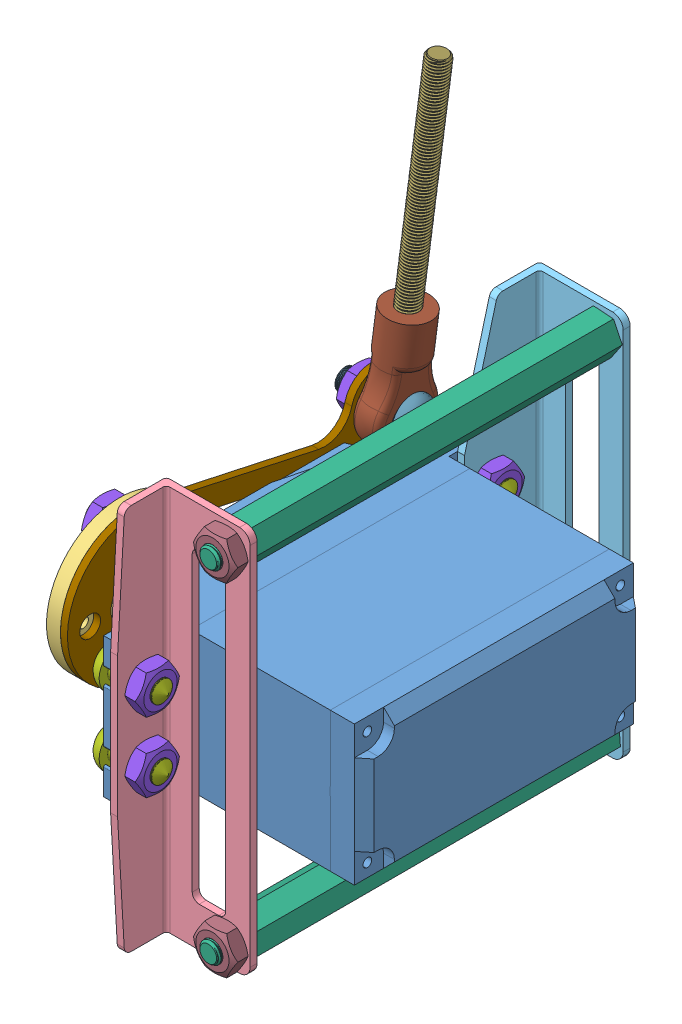
SolidWorks assembly 舵机装配, configuration 默认. Lengths in mm.
Overall size (50 100.66 64.22).
33 component instances, 14 part files, 67 mates.
Components (placement in the parent):
- 舵机-1: 舵机 [默认] at (-7.7618 -11.8937 34.529) size (40 20.22 54.02)
- 舵机齿轮-1: 舵机齿轮 [默认] at (-25.7618 -11.8937 63.729) x (0 0 -1) z (1 0 0) size (5.77 5.77 4)
- 舵机摆臂连接件-1: 舵机摆臂连接件 [默认] at (-23.2618 -11.8937 63.729) x (0 -0.05131 0.998683) z (-1 0 0) size (21 21 6.01)
- 舵机支架-上-1: 舵机支架-上 [默认] at (2.2382 -11.8937 75.034) x (0 1 0) z (0 0 1) size (55.4 13 8)
- 舵机支架-下-1: 舵机支架-下 [默认] at (2.2382 -11.8937 21.534) x (0 1 0) z (0 0 1) size (55.4 13 11.75)
- 铜柱-舵机-1: 铜柱-舵机 [默认] at (-0.7618 -36.3937 22.534) x (0.003125 0.999995 0) z (0 0 1) size (5.75 5.22 56.58)
- 铜柱-舵机-2: 铜柱-舵机 [默认] at (-0.7618 12.6063 22.534) x (0.625891 0.77991 0) z (0 0 1) size (5.75 5.22 56.58)
- 十字半圆头螺钉-M3-1: 十字半圆头螺钉-M3 [GB_WOOD_SCREWS_TYPE136 M3X8-N] at (-15.6318 -6.8937 79.284) size (9.31 5.8 5.8)
- 十字半圆头螺钉-M3-3: 十字半圆头螺钉-M3 [GB_WOOD_SCREWS_TYPE136 M3X8-N] at (-15.6318 -16.8937 79.284) size (9.31 5.8 5.8)
- 十字半圆头螺钉-M3-4: 十字半圆头螺钉-M3 [GB_WOOD_SCREWS_TYPE136 M3X8-N] at (-15.6318 -6.8937 29.784) size (9.31 5.8 5.8)
- 十字半圆头螺钉-M3-5: 十字半圆头螺钉-M3 [GB_WOOD_SCREWS_TYPE136 M3X8-N] at (-15.6318 -16.8937 29.784) size (9.31 5.8 5.8)
- 六角螺母-M3-4: 六角螺母-M3 [GB_FASTENER_NUT_SNAB1 M3-C] at (-7.3618 -6.8937 29.784) x (0 0 -1) z (1 0 0) size (6.35 5.5 2.4)
- 六角螺母-M3-5: 六角螺母-M3 [GB_FASTENER_NUT_SNAB1 M3-C] at (-7.3618 -16.8937 29.784) x (0 0 -1) z (1 0 0) size (6.35 5.5 2.4)
- 六角螺母-M3-6: 六角螺母-M3 [GB_FASTENER_NUT_SNAB1 M3-C] at (-7.3618 -16.8937 79.284) x (0 0 -1) z (1 0 0) size (6.35 5.5 2.4)
- 六角螺母-M3-7: 六角螺母-M3 [GB_FASTENER_NUT_SNAB1 M3-C] at (-7.3618 -6.8937 79.284) x (0 0 -1) z (1 0 0) size (6.35 5.5 2.4)
- 舵机拉杆-1: 舵机拉杆 [默认] at (-26.7618 -10.1235 29.2744) x (0 0.998683 0.05131) z (1 0 0) size (21 49 1)
- 十字半圆头螺钉-M3-8: 十字半圆头螺钉-M3 [GB_WOOD_SCREWS_TYPE136 M3X8-N] at (-30.1318 -11.8937 63.729) size (9.31 5.8 5.8)
- 半球型活动头-1: 半球型活动头 [默认] at (-23.3618 -3.5233 26.8764) x (0 -0.381849 0.924225) z (0 0.924225 0.381849) size (5.8 4.8 5.8)
- 舵机拉杆球头-1: 舵机拉杆球头 [默认] at (-23.3618 -4.6307 29.5566) x (-0.080816 -0.995071 0.057468) z (-0.006326 0.058167 0.998287) size (17.5 6.4 9.4)
- 半球型活动头-2: 半球型活动头 [默认] at (-23.3618 -13.0321 27.676) x (0 -0.891063 0.453879) z (0 -0.453879 -0.891063) size (5.8 4.8 5.8)
- 舵机拉杆球头-2: 舵机拉杆球头 [默认] at (-23.3618 -15.6162 28.9922) x (-0.033008 0.983548 0.177606) z (-0.09339 -0.179961 0.979231) size (17.5 6.4 9.4)
- 丝杆-舵机-1: 丝杆-舵机 [默认] at (-19.7413 39.9485 26.9821) x (-0.977477 0.090401 0.1907) z (0.080816 0.995071 -0.057468) size (3.06 3.46 35.46)
- 丝杆-舵机-2: 丝杆-舵机 [默认] at (-23.0383 -25.255 27.2517) x (0.908978 -0.04434 0.41448) z (-0.033008 0.983548 0.177606) size (3.06 3.46 35.46)
- 六角螺母-M3-黄色-1: 六角螺母-M3-黄色 [GB_FASTENER_NUT_SNAB1 M3-C] at (-0.7618 12.6063 78.434) size (6.35 5.5 2.4)
- 六角螺母-M3-黄色-2: 六角螺母-M3-黄色 [GB_FASTENER_NUT_SNAB1 M3-C] at (-0.7618 -36.3937 78.434) size (6.35 5.5 2.4)
- 十字半圆头螺钉-M3-12: 十字半圆头螺钉-M3 [GB_WOOD_SCREWS_TYPE136 M3X8-N] at (-23.3918 -4.6532 64.101) x (-1 0 0) z (0 0.924225 0.381849) size (9.31 5.8 5.8)
- 六角螺母-M3-14: 六角螺母-M3 [GB_FASTENER_NUT_SNAB1 M3-C] at (-31.1618 -4.6532 64.101) x (0 0 1) z (-1 0 0) size (6.35 5.5 2.4)
- 十字半圆头长螺钉-M3-3: 十字半圆头长螺钉-M3 [GB_WOOD_SCREWS_TYPE136 M3X8-N] at (-18.5918 -4.6307 29.5566) x (-1 0 0) z (0 0.924225 0.381849) size (12.81 5.8 5.8)
- 十字半圆头长螺钉-M3-4: 十字半圆头长螺钉-M3 [GB_WOOD_SCREWS_TYPE136 M3X8-N] at (-18.5918 -15.6162 28.9922) x (-1 0 0) z (0 0.924225 0.381849) size (12.81 5.8 5.8)
- 六角螺母-M3-16: 六角螺母-M3 [GB_FASTENER_NUT_SNAB1 M3-C] at (-29.1618 -4.6307 29.5566) x (0 0 1) z (-1 0 0) size (6.35 5.5 2.4)
- 六角螺母-M3-17: 六角螺母-M3 [GB_FASTENER_NUT_SNAB1 M3-C] at (-29.1618 -15.6162 28.9922) x (0 0 1) z (-1 0 0) size (6.35 5.5 2.4)
- 十字半圆头螺钉-M3-14: 十字半圆头螺钉-M3 [GB_WOOD_SCREWS_TYPE136 M3X8-N] at (-23.3918 -19.1341 63.357) x (-1 0 0) z (0 0.924225 0.381849) size (9.31 5.8 5.8)
- 六角螺母-M3-18: 六角螺母-M3 [GB_FASTENER_NUT_SNAB1 M3-C] at (-31.1618 -19.1341 63.357) x (0 0 1) z (-1 0 0) size (6.35 5.5 2.4)
Mates (geometry in assembly coordinates):
- 重合1: coincident anti-aligned: plane of 舵机-1 through (-21.7618 -11.8937 63.729) normal (-1 0 0); plane of 舵机齿轮-1 through (-21.7618 -11.8937 63.729) normal (1 0 0)
- 同心2: concentric aligned: cylinder of 舵机-1 through (-21.7618 -11.8937 63.729) axis (-1 0 0) radius 2.95; cylinder of 舵机齿轮-1 through (-25.7618 -11.8937 63.729) axis (-1 0 0) radius 0.875
- 平行1: parallel anti-aligned: plane of 舵机齿轮-1 through (-25.7618 -11.8937 63.729) normal (-1 0 0); plane of 舵机摆臂连接件-1 through (-26.7618 -11.8937 63.729) normal (1 0 0)
- 距离1: distance = 46 mm anti-aligned: plane of 舵机摆臂连接件-1 through (-28.7618 -11.8937 63.729) normal (-1 0 0); plane of 舵机-1 through (17.2382 -1.8837 35.779) normal (1 0 0)
- 同心3: concentric aligned: cylinder of 舵机齿轮-1 through (-25.7618 -11.8937 63.729) axis (-1 0 0) radius 0.875; cylinder of 舵机摆臂连接件-1 through (-26.7618 -11.8937 63.729) axis (-1 0 0) radius 1.5
- 同心4: concentric anti-aligned: cylinder of 舵机-1 through (12.2392 -16.8937 29.784) axis (-1 0 0) radius 2.25; cylinder of 舵机支架-下-1 through (-10.7618 -16.8937 29.784) axis (1 0 0) radius 1.5
- 重合3: coincident anti-aligned: plane of 舵机支架-下-1 through (2.2382 -11.8937 22.534) normal (0 0 1); plane of 铜柱-舵机-2 through (-0.7618 12.6063 22.534) normal (0 0 -1)
- 同心6: concentric aligned: cylinder of 舵机支架-下-1 through (-0.7618 12.6063 22.534) axis (0 0 -1) radius 1.5; cylinder of 铜柱-舵机-2 through (-0.7618 12.6063 22.534) axis (0 0 -1) radius 1.25
- 重合4: coincident anti-aligned: plane of 舵机支架-下-1 through (2.2382 -11.8937 22.534) normal (0 0 1); plane of 铜柱-舵机-1 through (-0.7618 -36.3937 22.534) normal (0 0 -1)
- 同心7: concentric aligned: cylinder of 舵机支架-下-1 through (-0.7618 -36.3937 22.534) axis (0 0 -1) radius 1.5; cylinder of 铜柱-舵机-1 through (-0.7618 -36.3937 22.534) axis (0 0 -1) radius 1.25
- 同心8: concentric aligned: cylinder of 舵机支架-上-1 through (-0.7618 12.6063 76.034) axis (0 0 -1) radius 1.5; cylinder of 铜柱-舵机-2 through (-0.7618 12.6063 79.034) axis (0 0 -1) radius 1.5
- 重合6: coincident anti-aligned: plane of 舵机支架-上-1 through (2.2382 -11.8937 75.034) normal (0 0 -1); plane of 铜柱-舵机-2 through (-0.7618 12.6063 75.034) normal (0 0 1)
- 同心12: concentric anti-aligned: cylinder of 舵机-1 through (12.2392 -6.8937 29.784) axis (-1 0 0) radius 2.25; cylinder of 舵机支架-下-1 through (-10.7618 -6.8937 29.784) axis (1 0 0) radius 1.5
- 重合10: coincident anti-aligned: plane of 舵机-1 through (-10.7618 -1.8837 34.519) normal (1 0 0); plane of 舵机支架-下-1 through (-10.7618 15.8063 22.534) normal (-1 0 0)
- 同心13: concentric anti-aligned: cylinder of 舵机-1 through (12.2392 -6.8937 79.284) axis (-1 0 0) radius 2.25; cylinder of 舵机支架-上-1 through (-10.7618 -6.8937 79.284) axis (1 0 0) radius 1.5
- 同心141: concentric aligned: cylinder of 舵机-1 through (12.2392 -6.8937 79.284) axis (-1 0 0) radius 2.25; cylinder of 十字半圆头螺钉-M3-1 through (-29.2611 -6.8937 79.284) axis (-1 0 0) radius 1.5
- 重合111: coincident anti-aligned: plane of 舵机-1 through (-13.2618 -1.8837 74.539) normal (-1 0 0); plane of 十字半圆头螺钉-M3-1 through (-13.2618 -6.8937 77.784) normal (1 0 0)
- 同心161: concentric aligned: cylinder of 舵机-1 through (12.2392 -16.8937 79.284) axis (-1 0 0) radius 2.25; cylinder of 十字半圆头螺钉-M3-3 through (-29.2611 -16.8937 79.284) axis (-1 0 0) radius 1.5
- 重合131: coincident anti-aligned: plane of 舵机-1 through (-13.2618 -1.8837 74.539) normal (-1 0 0); plane of 十字半圆头螺钉-M3-3 through (-13.2618 -16.8937 77.784) normal (1 0 0)
- 同心171: concentric aligned: cylinder of 舵机-1 through (12.2392 -6.8937 29.784) axis (-1 0 0) radius 2.25; cylinder of 十字半圆头螺钉-M3-4 through (-29.2611 -6.8937 29.784) axis (-1 0 0) radius 1.5
- 重合141: coincident anti-aligned: plane of 舵机-1 through (-13.2618 -1.8837 27.519) normal (-1 0 0); plane of 十字半圆头螺钉-M3-4 through (-13.2618 -6.8937 28.284) normal (1 0 0)
- 同心181: concentric aligned: cylinder of 舵机-1 through (12.2392 -16.8937 29.784) axis (-1 0 0) radius 2.25; cylinder of 十字半圆头螺钉-M3-5 through (-29.2611 -16.8937 29.784) axis (-1 0 0) radius 1.5
- 重合151: coincident anti-aligned: plane of 舵机-1 through (-13.2618 -1.8837 27.519) normal (-1 0 0); plane of 十字半圆头螺钉-M3-5 through (-13.2618 -16.8937 28.284) normal (1 0 0)
- 同心191: concentric aligned: cylinder of 舵机支架-下-1 through (-10.7618 -6.8937 29.784) axis (1 0 0) radius 1.5; cone of 六角螺母-M3-4 through (-9.7618 -6.8937 29.784) axis (1 0 0)
- 重合161: coincident anti-aligned: plane of 舵机支架-下-1 through (-9.7618 15.8063 33.284) normal (1 0 0); plane of 六角螺母-M3-4 through (-9.7618 -6.8937 26.6086) normal (-1 0 0)
- 同心201: concentric aligned: cylinder of 舵机支架-下-1 through (-10.7618 -16.8937 29.784) axis (1 0 0) radius 1.5; cone of 六角螺母-M3-5 through (-9.7618 -16.8937 29.784) axis (1 0 0)
- 重合171: coincident anti-aligned: plane of 舵机支架-下-1 through (-9.7618 15.8063 33.284) normal (1 0 0); plane of 六角螺母-M3-5 through (-9.7618 -16.8937 26.6086) normal (-1 0 0)
- 同心211: concentric aligned: cylinder of 舵机支架-上-1 through (-10.7618 -16.8937 79.284) axis (1 0 0) radius 1.5; cone of 六角螺母-M3-6 through (-9.7618 -16.8937 79.284) axis (1 0 0)
- 重合181: coincident anti-aligned: plane of 舵机支架-上-1 through (-9.7618 15.8063 83.034) normal (1 0 0); plane of 六角螺母-M3-6 through (-9.7618 -16.8937 76.1086) normal (-1 0 0)
- 同心221: concentric aligned: cylinder of 舵机支架-上-1 through (-10.7618 -6.8937 79.284) axis (1 0 0) radius 1.5; cone of 六角螺母-M3-7 through (-9.7618 -6.8937 79.284) axis (1 0 0)
- 重合191: coincident anti-aligned: plane of 舵机支架-上-1 through (-9.7618 15.8063 83.034) normal (1 0 0); plane of 六角螺母-M3-7 through (-9.7618 -6.8937 76.1086) normal (-1 0 0)
- 重合20: coincident anti-aligned: plane of 舵机拉杆-1 through (-26.7618 -15.6162 28.9922) normal (-1 0 0); plane of 舵机摆臂连接件-1 through (-26.7618 -11.8937 63.729) normal (1 0 0)
- 同心23: concentric aligned: cylinder of 舵机摆臂连接件-1 through (-27.7618 -11.8937 63.729) axis (-1 0 0) radius 3; cylinder of 舵机拉杆-1 through (-25.7618 -11.8937 63.729) axis (-1 0 0) radius 4.25
- 同心281: concentric aligned: cylinder of 舵机摆臂连接件-1 through (-26.7618 -11.8937 63.729) axis (-1 0 0) radius 1.5; cylinder of 十字半圆头螺钉-M3-8 through (-43.7611 -11.8937 63.729) axis (-1 0 0) radius 1.5
- 重合251: coincident anti-aligned: plane of 舵机摆臂连接件-1 through (-27.7618 -11.8937 63.729) normal (-1 0 0); plane of 十字半圆头螺钉-M3-8 through (-27.7618 -11.8937 62.229) normal (1 0 0)
- 同心33: concentric: sphere of 半球型活动头-1; sphere of 舵机拉杆球头-1
- 同心41: concentric: sphere of 半球型活动头-2; sphere of 舵机拉杆球头-2
- 同心42: concentric aligned: cylinder of 舵机拉杆球头-1 through (-22.3274 8.1062 28.8211) axis (0.080816 0.995071 -0.057468) radius 1.25; cylinder of 丝杆-舵机-1 through (-22.5698 5.121 28.9935) axis (0.080816 0.995071 -0.057468) radius 1.5
- 距离2: distance = 3 mm anti-aligned: plane of 丝杆-舵机-1 through (-22.5698 5.121 28.9935) normal (-0.080816 -0.995071 0.057468); plane of 舵机拉杆球头-1 through (-22.3274 8.1062 28.8211) normal (0.080816 0.995071 -0.057468)
- 距离3: distance = 3 mm anti-aligned: plane of 丝杆-舵机-2 through (-23.0383 -25.255 27.2517) normal (-0.033008 0.983548 0.177606); plane of 舵机拉杆球头-2 through (-22.9393 -28.2056 26.7189) normal (0.033008 -0.983548 -0.177606)
- 同心43: concentric anti-aligned: cylinder of 舵机拉杆球头-2 through (-22.9393 -28.2056 26.7189) axis (0.033008 -0.983548 -0.177606) radius 1.25; cylinder of 丝杆-舵机-2 through (-21.8831 -59.6792 21.0355) axis (-0.033008 0.983548 0.177606) radius 1.5
- 同心3521: concentric anti-aligned: cylinder of 舵机支架-上-1 through (-0.7618 12.6063 76.034) axis (0 0 -1) radius 1.5; cone of 六角螺母-M3-黄色-1 through (-0.7618 12.6063 76.034) axis (0 0 1)
- 重合3021: coincident anti-aligned: plane of 舵机支架-上-1 through (2.2382 -11.8937 76.034) normal (0 0 1); plane of 六角螺母-M3-黄色-1 through (2.4136 12.6063 76.034) normal (0 0 -1)
- 同心3531: concentric anti-aligned: cylinder of 舵机支架-上-1 through (-0.7618 -36.3937 76.034) axis (0 0 -1) radius 1.5; cone of 六角螺母-M3-黄色-2 through (-0.7618 -36.3937 76.034) axis (0 0 1)
- 重合3031: coincident anti-aligned: plane of 舵机支架-上-1 through (2.2382 -11.8937 76.034) normal (0 0 1); plane of 六角螺母-M3-黄色-2 through (2.4136 -36.3937 76.034) normal (0 0 -1)
- 重合3033: coincident aligned: plane of 舵机-1 through (-7.7618 -11.8937 34.529) normal (0 1 0); plane of 舵机齿轮-1
- 同心35361: concentric anti-aligned: cylinder of 舵机拉杆-1 through (-25.7618 -4.6532 64.101) axis (-1 0 0) radius 1.5; cylinder of 十字半圆头螺钉-M3-12 through (-9.7626 -4.6532 64.101) axis (1 0 0) radius 1.5
- 重合30371: coincident anti-aligned: plane of 舵机拉杆-1 through (-25.7618 -15.6162 28.9922) normal (1 0 0); plane of 十字半圆头螺钉-M3-12 through (-25.7618 -6.0395 63.5282) normal (-1 0 0)
- 同心3537: concentric anti-aligned: cylinder of 舵机摆臂连接件-1 through (-23.2618 -4.6532 64.101) axis (-1 0 0) radius 0.75; cylinder of 十字半圆头螺钉-M3-12 through (-9.7626 -4.6532 64.101) axis (1 0 0) radius 1.5
- 同心35391: concentric anti-aligned: cylinder of 十字半圆头螺钉-M3-12 through (-9.7626 -4.6532 64.101) axis (1 0 0) radius 1.5; cone of 六角螺母-M3-14 through (-28.7618 -4.6532 64.101) axis (-1 0 0)
- 重合30391: coincident anti-aligned: plane of 舵机摆臂连接件-1 through (-28.7618 -11.8937 63.729) normal (-1 0 0); plane of 六角螺母-M3-14 through (-28.7618 -4.6532 67.2764) normal (1 0 0)
- 重合3043: coincident anti-aligned: plane of 舵机拉杆-1 through (-25.7618 -15.6162 28.9922) normal (1 0 0); plane of 半球型活动头-2 through (-25.7618 -11.8963 32.7087) normal (-1 0 0)
- 重合3044: coincident anti-aligned: plane of 舵机拉杆-1 through (-25.7618 -15.6162 28.9922) normal (1 0 0); plane of 半球型活动头-1 through (-25.7618 -8.6302 26.1429) normal (-1 0 0)
- 同心354031: concentric aligned: cylinder of 半球型活动头-1 through (-25.7618 -4.6307 29.5566) axis (1 0 0) radius 1.5; cylinder of 十字半圆头长螺钉-M3-3 through (-4.9626 -4.6307 29.5566) axis (1 0 0) radius 1.5
- 重合30461: coincident anti-aligned: plane of 半球型活动头-1 through (-20.9618 -8.6302 26.1429) normal (1 0 0); plane of 十字半圆头长螺钉-M3-3 through (-20.9618 -6.017 28.9839) normal (-1 0 0)
- 同心35404: concentric aligned: cylinder of 舵机拉杆-1 through (-25.7618 -15.6162 28.9922) axis (-1 0 0) radius 1.5; cylinder of 半球型活动头-2 through (-20.9618 -15.6162 28.9922) axis (-1 0 0) radius 1.5
- 同心354051: concentric anti-aligned: cylinder of 半球型活动头-2 through (-20.9618 -15.6162 28.9922) axis (-1 0 0) radius 1.5; cylinder of 十字半圆头长螺钉-M3-4 through (-4.9626 -15.6162 28.9922) axis (1 0 0) radius 1.5
- 重合30471: coincident anti-aligned: plane of 半球型活动头-2 through (-20.9618 -11.8963 32.7087) normal (1 0 0); plane of 十字半圆头长螺钉-M3-4 through (-20.9618 -17.0025 28.4195) normal (-1 0 0)
- 同心354061: concentric anti-aligned: cylinder of 十字半圆头长螺钉-M3-3 through (-4.9626 -4.6307 29.5566) axis (1 0 0) radius 1.5; cone of 六角螺母-M3-16 through (-26.7618 -4.6307 29.5566) axis (-1 0 0)
- 重合30481: coincident anti-aligned: plane of 舵机拉杆-1 through (-26.7618 -15.6162 28.9922) normal (-1 0 0); plane of 六角螺母-M3-16 through (-26.7618 -4.6307 32.7321) normal (1 0 0)
- 同心354071: concentric aligned: cone of 六角螺母-M3-17 through (-26.7618 -15.6162 28.9922) axis (-1 0 0); cylinder of 舵机拉杆-1 through (-25.7618 -15.6162 28.9922) axis (-1 0 0) radius 1.5
- 重合30491: coincident anti-aligned: plane of 舵机拉杆-1 through (-26.7618 -15.6162 28.9922) normal (-1 0 0); plane of 六角螺母-M3-17 through (-26.7618 -15.6162 32.1677) normal (1 0 0)
- 同心35408: concentric anti-aligned: cylinder of 舵机拉杆-1 through (-25.7618 -4.6307 29.5566) axis (-1 0 0) radius 1.5; cylinder of 十字半圆头长螺钉-M3-3 through (-4.9626 -4.6307 29.5566) axis (1 0 0) radius 1.5
- 同心3540731: concentric anti-aligned: cylinder of 舵机拉杆-1 through (-25.7618 -19.1341 63.357) axis (-1 0 0) radius 1.5; cylinder of 十字半圆头螺钉-M3-14 through (-9.7626 -19.1341 63.357) axis (1 0 0) radius 1.5
- 重合304931: coincident anti-aligned: plane of 舵机拉杆-1 through (-25.7618 -15.6162 28.9922) normal (1 0 0); plane of 十字半圆头螺钉-M3-14 through (-25.7618 -20.5204 62.7842) normal (-1 0 0)
- 同心3540741: concentric anti-aligned: cylinder of 十字半圆头螺钉-M3-14 through (-9.7626 -19.1341 63.357) axis (1 0 0) radius 1.5; cone of 六角螺母-M3-18 through (-28.7618 -19.1341 63.357) axis (-1 0 0)
- 重合304941: coincident anti-aligned: plane of 舵机摆臂连接件-1 through (-28.7618 -11.8937 63.729) normal (-1 0 0); plane of 六角螺母-M3-18 through (-28.7618 -19.1341 66.5324) normal (1 0 0)
